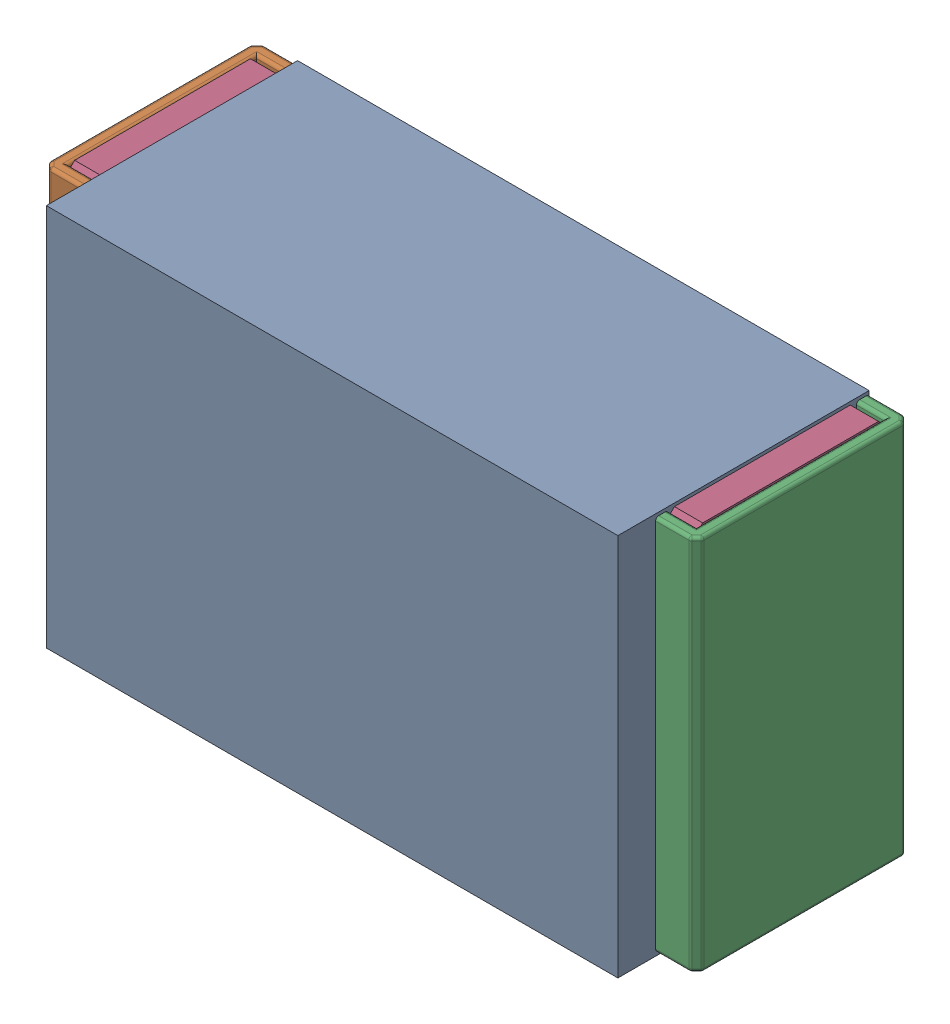
SolidWorks assembly R8, configuration Default. Lengths in mm.
Overall size (1.04 0.61 0.4).
3 component instances, 2 part files, 0 mates.
Components (placement in the parent):
- 1088880352-1: 1088880352 [Default] at (4.55 37.675 0) size (0.91 0.61 0.4)
  - Extruded-28-1: Extruded-28 [Default] at origin size (0.91 0.61 0.4)
- R0402-1: R0402 [Default] at (4.55 37.675 0) x (-1 0 0) z (0 1 0) size (1.04 0.34 0.6)
